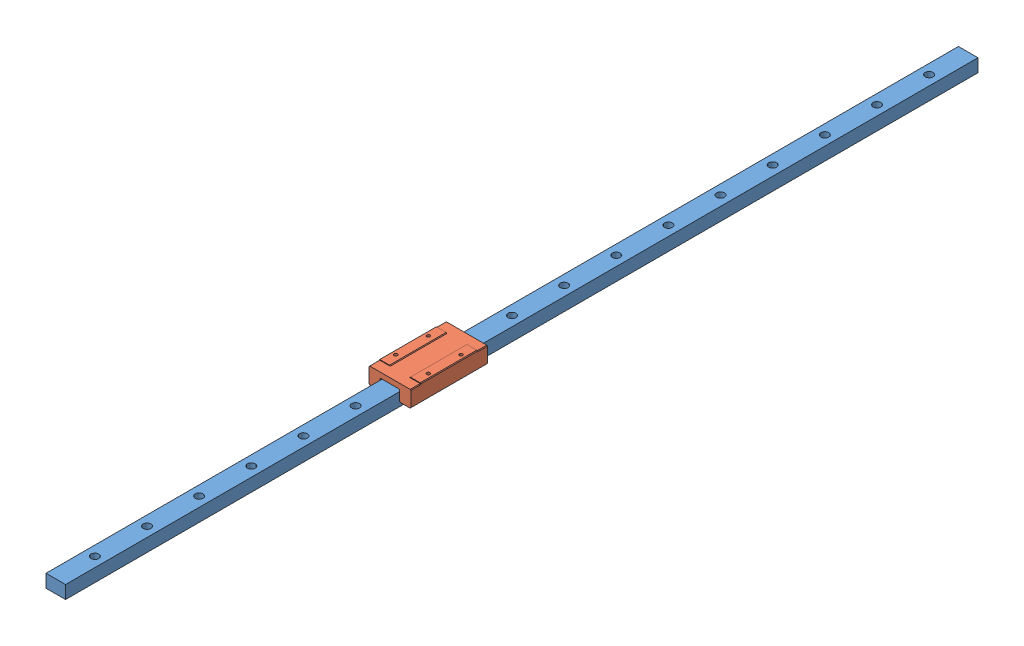
SolidWorks assembly MGN15_H_700, configuration Default. Lengths in mm.
Overall size (32 16 700).
2 component instances, 2 part files, 3 mates.
Components (placement in the parent):
- MGN15_rail_700-1: MGN15_rail_700 [Default] at origin size (15 10 700)
- MGN15H_carriage_block)-1: MGN15H_carriage_block) [Default] at (-8.5 3 443.6553) size (32 13 58.8)
Mates (geometry in assembly coordinates):
- Distance2: distance = 3 mm aligned: plane of MGN15_rail_700-1 through (0 0 700) normal (0 -1 0); plane of MGN-15H-1 through (-8.5 3 443.6553) normal (0 -1 0)
- Width3: width anti-aligned: plane of MGN-15H-1 through (0 3 384.8553) normal (1 0 0); plane of MGN15_rail_700-1 through (15 3 384.8553) normal (-1 0 0); plane of MGN-15H-1 through (0 0 700) normal (-1 0 0); plane of MGN15_rail_700-1 through (15 0 700) normal (1 0 0)
- Width4: width = 640.5588 mm aligned: plane of MGN15_rail_700-1 through (0 0 700) normal (0 0 1); plane of MGN-15H-1 through (0 0 0) normal (0 0 -1); plane of MGN15_rail_700-1 through (-8.5 16 443.6553) normal (0 0 1); plane of MGN-15H-1 through (-8.5 16 384.8553) normal (0 0 -1)
